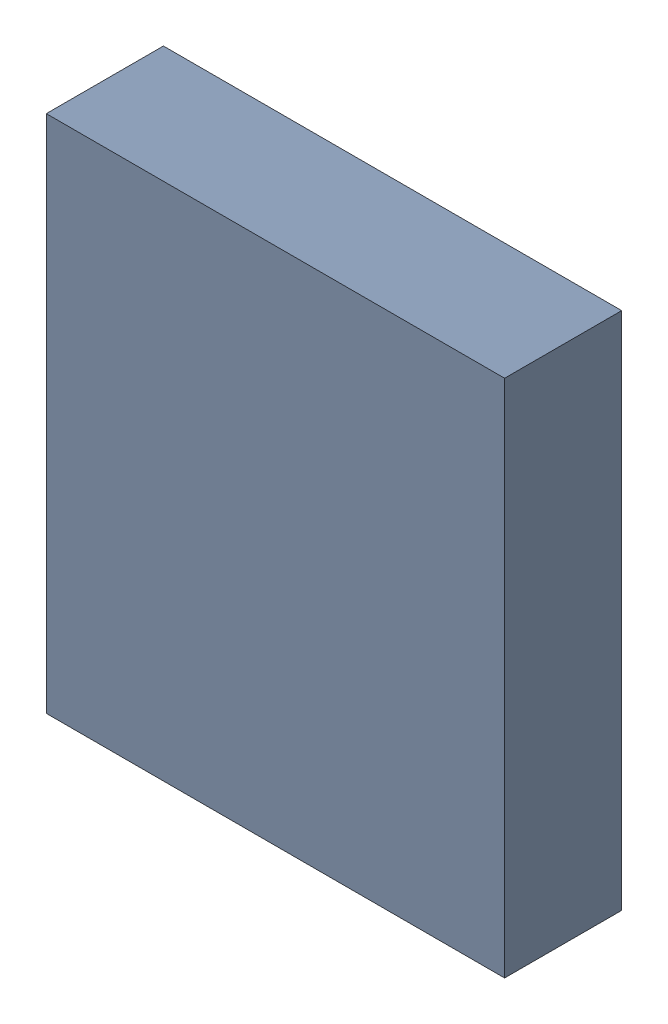
SolidWorks assembly U700PCB, configuration Default. Lengths in mm.
Overall size (4.5 5.1 1.15).
2 component instances, 1 part files, 0 mates.
Components (placement in the parent):
- 846483832-1: 846483832 [Default] at (109.4 121.5 -2.8638) size (4.5 5.1 1.15)
  - Extruded_18-1: Extruded_18 [Default] at origin size (4.5 5.1 1.15)
